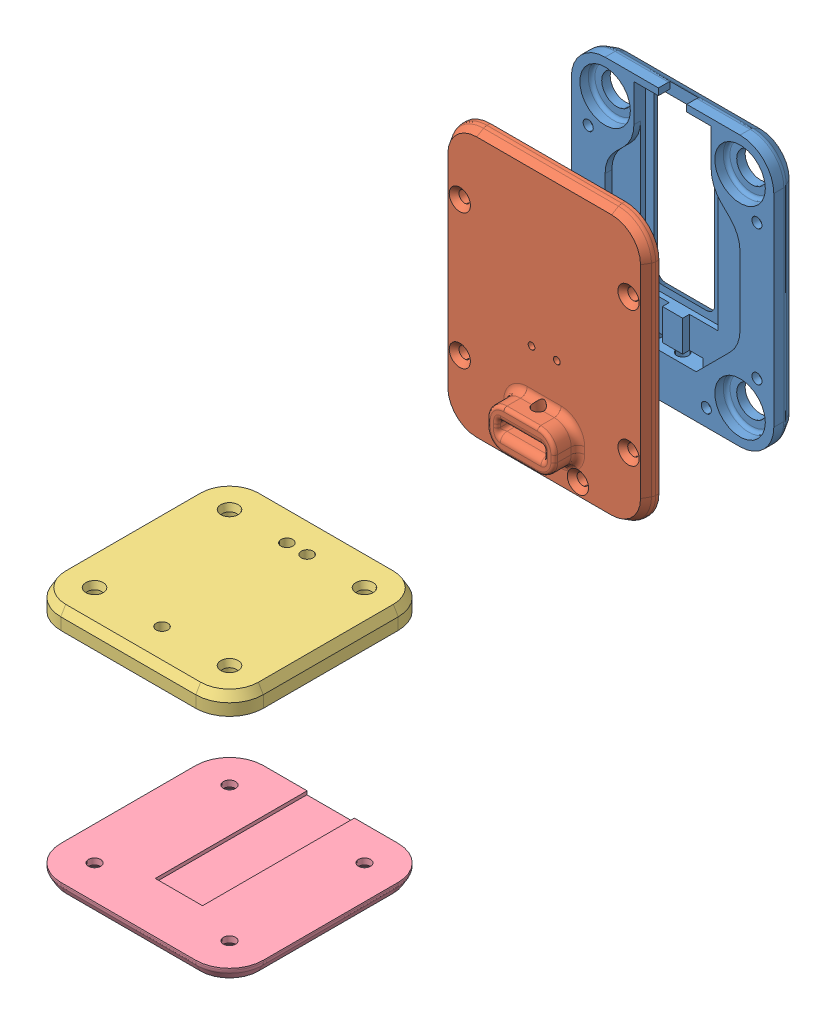
SolidWorks assembly Assembly, configuration Default. Lengths in mm.
Overall size (60 134.64 167.3).
4 component instances, 4 part files, 7 mates.
Components (placement in the parent):
- Base-1: Base [Default] at (13.6638 76.2016 69.364) size (60 80 6)
- Base-tampa-1: Base-tampa [Default] at (13.6638 76.2016 109.411) size (60 80 11.01)
- Corpo-1: Corpo [Default] at (13.6638 17.7016 206.6689) x (-1 0 0) z (0 -1 0) size (60 60 6)
- Tampa-1: Tampa [Default] at (13.6638 -56.4434 206.6689) x (1 0 0) z (0 1 0) size (60 60 3.5)
Mates (geometry in assembly coordinates):
- Concentric1: concentric anti-aligned: cylinder of Base-1 through (38.6638 58.2016 69.364) axis (0 0 -1) radius 1.5; cylinder of Base-tampa-1 through (38.6638 58.2016 113.411) axis (0 0 1) radius 1.7
- Concentric2: concentric anti-aligned: cylinder of Base-1 through (-11.3362 58.2016 69.364) axis (0 0 -1) radius 1.5; cylinder of Base-tampa-1 through (-11.3362 58.2016 113.411) axis (0 0 1) radius 1.7
- Concentric3: concentric anti-aligned: cylinder of Corpo-1 through (33.6638 17.7016 186.6689) axis (0 1 0) radius 1.5; cylinder of Tampa-1 through (33.6638 -56.4434 186.6689) axis (0 -1 0) radius 1.8
- Concentric4: concentric anti-aligned: cylinder of Corpo-1 through (-6.3362 17.7016 226.6689) axis (0 1 0) radius 1.5; circle of Tampa-1
- Coincident3: coincident aligned: plane of Base-tampa-1 through (7.6638 13.7016 109.411) normal (0 -1 0); plane of Corpo-1 through (20.6638 13.7016 176.6689) normal (0 -1 0)
- Parallel3: parallel anti-aligned: line of Base-1 through (9.4638 78.2016 75.364) axis (-1 0 0); line of Corpo-1 through (-6.3362 15.2016 176.6689) axis (1 0 0)
- Coincident7: coincident aligned: plane of Base-1 through (-16.3362 68.2016 75.364) normal (-1 0 0); plane of Corpo-1 through (-16.3362 11.7016 186.6689) normal (-1 0 0)
